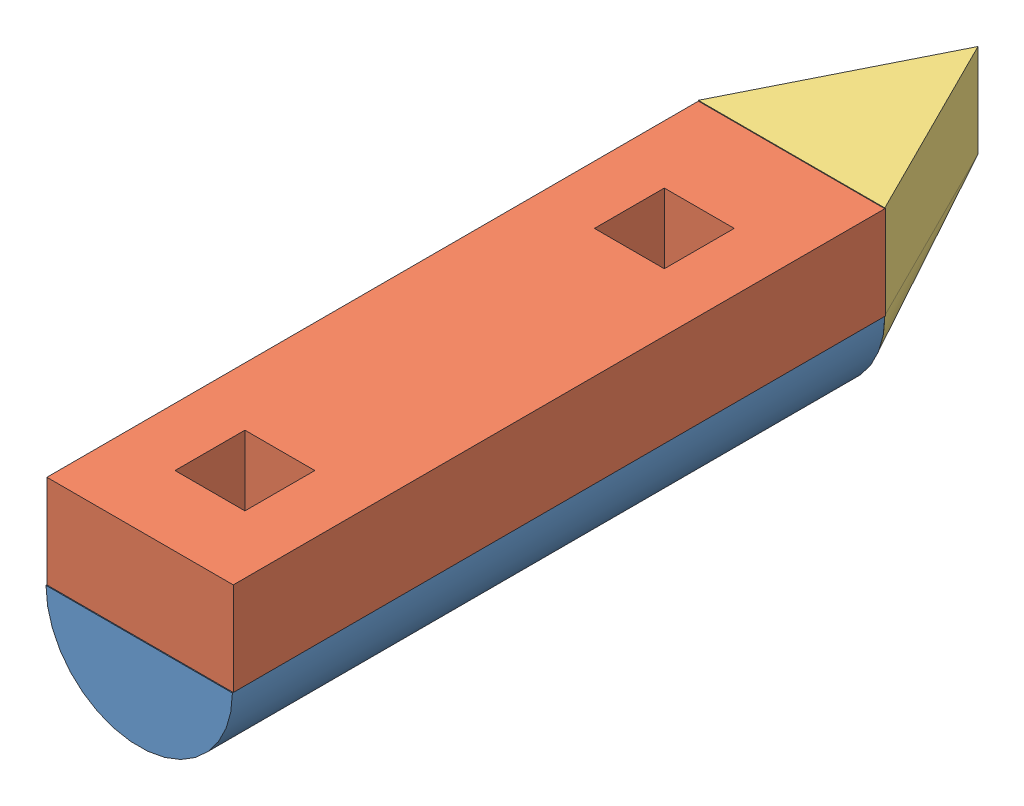
SolidWorks assembly pontoon assembly, configuration Default(1). Lengths in mm.
Overall size (203.2 203.96 914.4).
3 component instances, 3 part files, 2 mates.
Components (placement in the parent):
- HALF CYLINDER-1: HALF CYLINDER [Default] at (266.6447 372.2626 223.4401) size (203.2 101.6 711.2)
- RECTANGULER-1: RECTANGULER [Default] at (165.0447 372.2626 222.4801) size (203.2 101.6 711.2)
- HALF CONE-1: HALF CONE [Default] at (266.6447 373.0192 156.7651) x (1 0 0) z (0 1 0) size (203.2 203.2 203.2)
Mates (geometry in assembly coordinates):
- Coincident5: coincident anti-aligned: plane of HALF CYLINDER-1 through (165.0447 372.2626 934.6401) normal (0 1 0); plane of RECTANGULER-1 through (165.0447 372.2626 933.6801) normal (0 -1 0)
- Coincident8: coincident anti-aligned: plane of HALF CYLINDER-1 through (266.6447 372.2626 223.4401) normal (0 0 -1); plane of HALF CONE-1 through (368.2447 373.0192 223.4401) normal (0 0 1)
